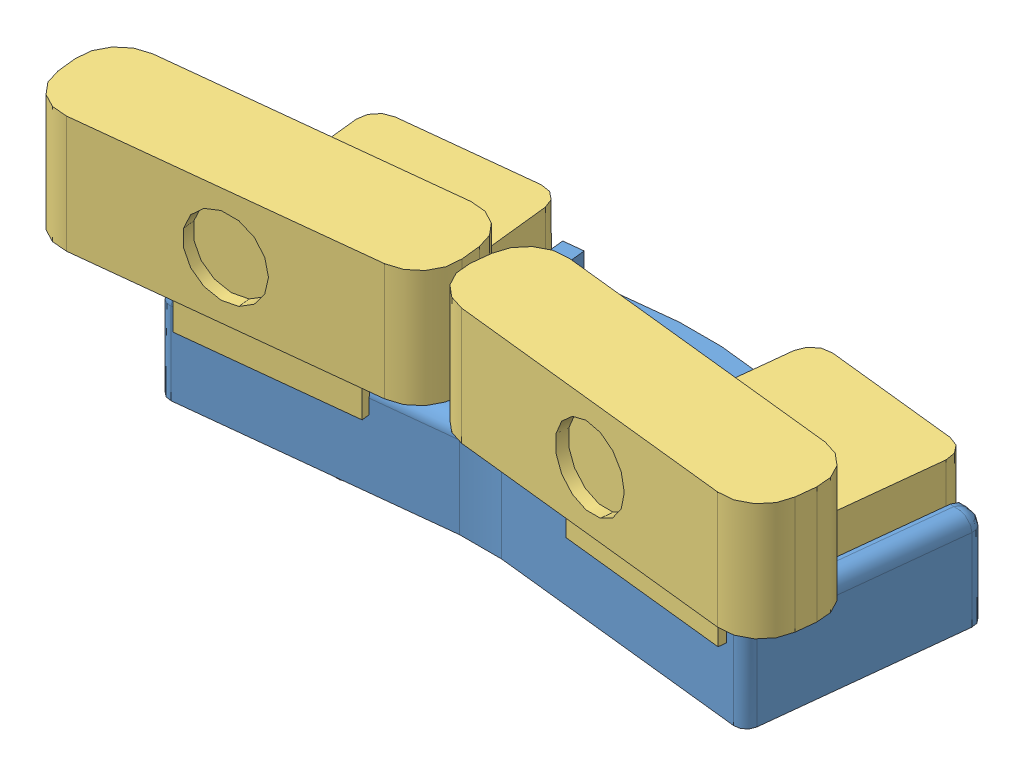
SolidWorks assembly Assem1, configuration Default. Lengths in mm.
Overall size (201.93 82.2 80.42).
5 component instances, 3 part files, 10 mates.
Components (placement in the parent):
- camholder-1: camholder [Default] at (53.263 76.0117 121.113) size (161.55 25 63.88)
- arm-1: arm [Default] at (2.263 79.0752 106.5382) x (0.900972 0 -0.433878) z (0.433878 0 0.900972) size (15 41.2 15)
- arm-2: arm [Default] at (104.263 79.0752 106.5382) x (0.833596 0 0.552375) z (-0.552375 0 0.833596) size (15 41.2 15)
- camera-1: camera [Default] at (1.7228 95.2752 101.5675) x (0.994145 0 -0.108051) z (0.108051 0 0.994145) size (94 48 70.15)
- camera-2: camera [Default] at (104.8033 95.2752 101.5675) x (0.994145 0 0.108051) z (-0.108051 0 0.994145) size (94 48 70.15)
Mates (geometry in assembly coordinates):
- Concentric1: concentric anti-aligned: cylinder of camholder-1 through (104.263 95.0117 106.5382) axis (0 -1 0) radius 6.25; cylinder of arm-2 through (104.263 104.3445 106.5382) axis (0 1 0) radius 6
- Concentric2: concentric anti-aligned: cylinder of camholder-1 through (2.263 95.0117 106.5382) axis (0 -1 0) radius 6.25; cylinder of arm-1 through (2.263 104.3445 106.5382) axis (0 1 0) radius 6
- Concentric3: concentric anti-aligned: cylinder of arm-1 through (2.263 104.3445 106.5382) axis (0 1 0) radius 2.5; cylinder of camera-1 through (2.263 105.2752 106.5382) axis (0 -1 0) radius 2.5
- Parallel1: parallel anti-aligned: plane of camholder-1 through (-22.8497 152.3188 79.091) normal (0.994145 0 -0.108051); plane of camera-1 through (-22.8497 105.2752 79.091) normal (-0.994145 0 0.108051)
- Concentric4: concentric anti-aligned: cylinder of arm-2 through (104.263 104.3445 106.5382) axis (0 1 0) radius 2.5; cylinder of camera-2 through (104.263 105.2752 106.5382) axis (0 -1 0) radius 2.5
- Parallel2: parallel anti-aligned: plane of camholder-1 through (129.3758 152.3188 79.091) normal (-0.994145 0 -0.108051); plane of camera-2 through (129.3758 105.2752 79.091) normal (0.994145 0 0.108051)
- Coincident7: coincident anti-aligned: plane of arm-2 through (104.263 95.2752 106.5382) normal (0 1 0); plane of camera-2 through (104.8033 95.2752 101.5675) normal (0 -1 0)
- Coincident8: coincident anti-aligned: plane of arm-1 through (2.263 95.2752 106.5382) normal (0 1 0); plane of camera-1 through (1.7228 95.2752 101.5675) normal (0 -1 0)
- Tangent1: tangent: torus of camholder-1; plane of arm-2 through (104.263 91.0752 106.5382) normal (0 -1 0)
- Tangent2: tangent: torus of camholder-1; plane of arm-1 through (2.263 91.0752 106.5382) normal (0 -1 0)
